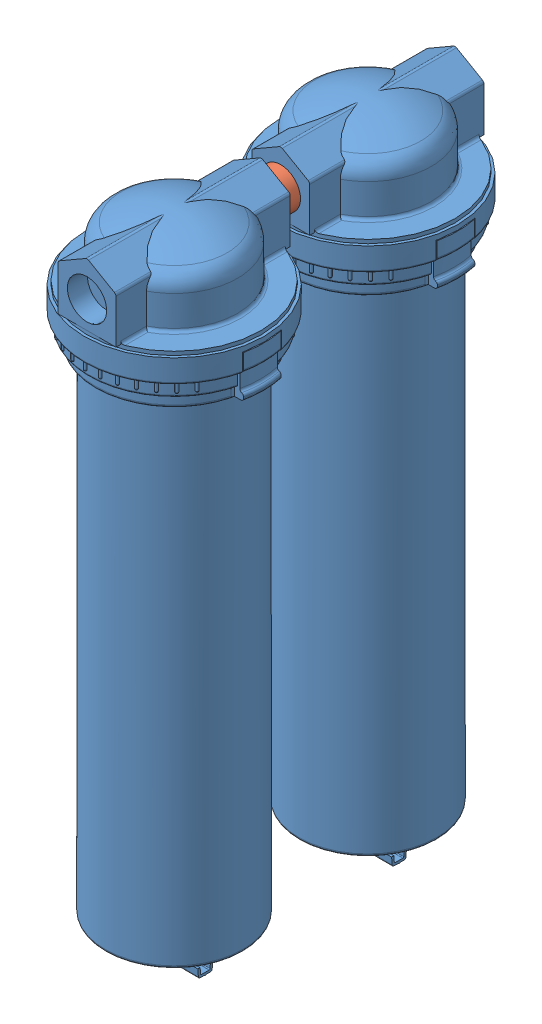
SolidWorks assembly ReadingTech_3P-150-M06-DCP, configuration Default. Lengths in mm.
Overall size (121.86 439.41 252.73).
3 component instances, 2 part files, 3 mates.
Components (placement in the parent):
- ReadingTech_3P-150-M06-P-1: ReadingTech_3P-150-M06-P [Default] at (119.9432 68.3928 338.4978) size (121.86 439.41 121.67)
- ReadingTech- 90,150cfm_connector_.75in-1: ReadingTech- 90,150cfm_connector_.75in [Default] at (119.9432 457.3938 279.5698) x (-0.923728 -0.383049 0) z (0.383049 -0.923728 0) size (26.67 13.21 26.67)
- ReadingTech_3P-150-M06-P-2: ReadingTech_3P-150-M06-P [Default] at (119.9432 68.3928 207.4338) size (121.86 439.41 121.67)
Mates (geometry in assembly coordinates):
- Coincident1: coincident anti-aligned: circle of ReadingTech- 90,150cfm_connector_.75in-1; circle of ReadingTech_3P-150-M06-P-2
- Coincident2: coincident aligned: circle of ReadingTech_3P-150-M06-P-1; circle of ReadingTech- 90,150cfm_connector_.75in-1
- Coincident3: coincident aligned: plane of ReadingTech_3P-150-M06-P-1 through (139.5012 470.0938 397.4258) normal (1 0 0); plane of ReadingTech_3P-150-M06-P-2 through (139.5012 470.0938 266.3618) normal (1 0 0)
